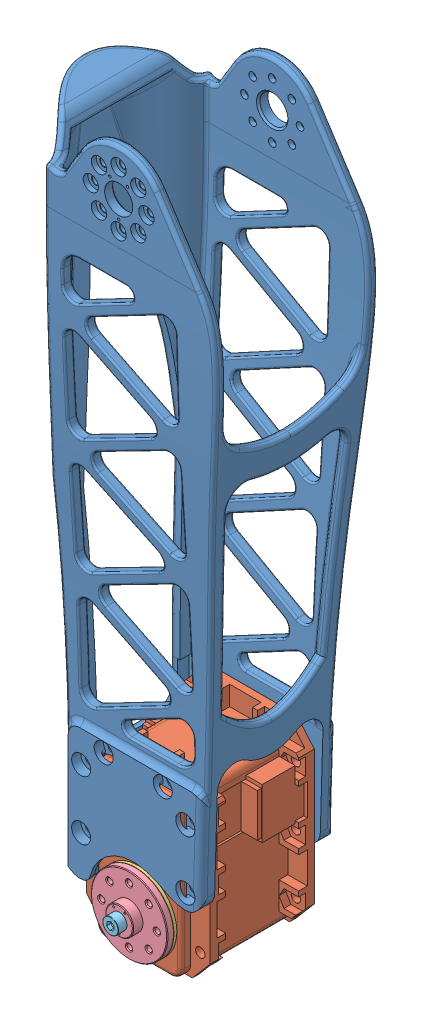
SolidWorks assembly shin, configuration left_MX28. Lengths in mm.
Overall size (66.2 208.53 50.97).
10 component instances, 8 part files, 6 mates.
Components (placement in the parent):
- shin-1: shin [MX28 - MX28] at (-29.7714 -82.05 0) size (66.2 192.04 50.24)
- MX-28-1: MX-28 [U] at (-29.7714 -82.05 0) x (-1 0 0) z (0 0 1) size (35.6 54.13 48.5)
  - dynamixel_x28series-1: dynamixel_x28series [U] at origin size (35.6 50.71 41.85)
  - trust_washer-1: trust_washer [U] at (0 0 18.6) x (-0.666375 -0.745617 0) z (0.745617 -0.666375 0) size (22 0.85 22)
  - HN07-N101-1: HN07-N101 [U] at (0 0 18.5) x (1 0 0) z (0 -1 0) size (22 5.85 22)
  - WB_M2.5x8-1: WB_M2.5x8 [ISO 4762 M2.5 x 8 --- 8N] at (0 0 25.85) x (0 0 -1) z (-0.991137 0.132843 0) size (10.5 4.5 4.5)
  - RX28-CAP-1: RX28-CAP [Défaut] at (0 0 -20.35) x (-0.995735 -0.092256 0) z (0 0 -1) size (7.2 7.2 1.8)
  - MF106ZZ-1: MF106ZZ [Défaut] at (0 0 -20.35) x (0.888333 -0.4592 0) z (-0.4592 -0.888333 0) size (11.2 3 11.2)
  - WB_M2.5x8-3: WB_M2.5x8 [ISO 4762 M2.5 x 8 --- 8N] at (0 0 -22.65) x (0 0 1) z (-0.936501 0.350665 0) size (10.5 4.5 4.5)
  - HN07-i101-1: HN07-i101 [Défaut] at (0 0 -20.5) x (1 0 0) z (0 1 0) size (22 3.05 22)
Mates (geometry in assembly coordinates):
- Coincident1: coincident aligned: plane of shin-1 through (-29.7714 -82.05 0) normal (0 0 1); plane of MX-28-1/dynamixel_x28series-1 through (-29.7714 -82.05 0) normal (0 0 1)
- Coincident2: coincident aligned: line of shin-1 through (-29.7714 -82.05 -29.7913) axis (0 0 1); line of MX-28-1/dynamixel_x28series-1 through (-29.7714 -82.05 -27.2811) axis (0 0 1)
- Parallel1: parallel anti-aligned: plane of shin-1 through (-29.7714 -82.05 0) normal (1 0 0); plane of MX-28-1/dynamixel_x28series-1
- Coincident3: coincident anti-aligned: plane of shin-1 through (-29.7714 -82.05 0) normal (0 0 1); plane of ? through (-3.3974 -51.1818 0) normal (0 0 -1)
- Coincident4: coincident anti-aligned: line of shin-1 through (-29.7714 -82.05 -29.7913) axis (0 0 1); line of ? through (-29.7714 -82.05 27.2811) axis (0 0 -1)
- Coincident5: coincident aligned: plane of shin-1 through (-29.7714 -82.05 0) normal (1 0 0); plane of ?
